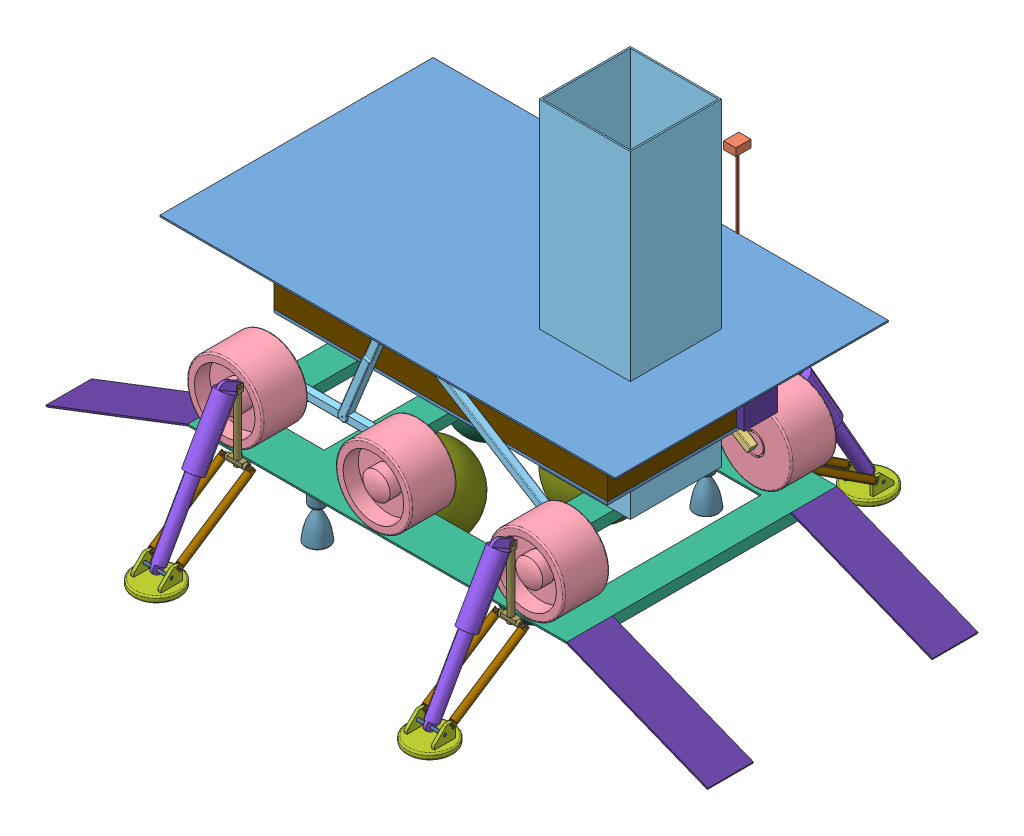
SolidWorks assembly Rover Lander assem_rev2, configuration Default. Lengths in mm.
Overall size (4365.19 2993.73 3190.9).
84 component instances, 35 part files, 46 mates.
Components (placement in the parent):
- Rover_base-1: Rover_base [Default] at (-1064.6676 -0.8898 562.4151) size (2200 20 1100)
- Neutron_spectrometer-1: Neutron_spectrometer [Default] at (-926.7762 19.1102 412.2415) size (300 57 300)
- Neutron_spectrometer_electronics-1: Neutron_spectrometer_electronics [Default] at (-591.6675 19.1102 476.7062) size (180 30 130)
- gc-1: gc [Default] at (-1085.6976 19.1102 139.436) size (100 80 100)
- svr_box-1: svr_box [Default] at (435.3324 -257.9063 312.4151) size (600 2100 600)
- xrf-1: xrf [Default] at (-995.9409 19.1102 -179.1913) size (80 90 80)
- geotechnical_exp-1: geotechnical_exp [Default] at (118.8439 19.1102 479.7148) x (0.999975 0 -0.007135) z (0.007135 0 0.999975) size (130 30 130)
- penetrometer_3-1: penetrometer_3 [Default] at (226.7911 19.1102 -521.6787) x (-0.361814 0 0.93225) z (-0.93225 0 -0.361814) size (20 40 20)
- penetrometer_3-2: penetrometer_3 [Default] at (171.3766 19.1102 -523.8951) size (20 40 20)
- penetrometer_3-3: penetrometer_3 [Default] at (128.071 19.1102 -518.5402) x (0.588244 0 -0.808683) z (0.808683 0 0.588244) size (20 40 20)
- power-1: power [Default] at (-492.3956 19.1102 -328.3877) size (180 90 96)
- geotechnical_exp_vane-1: geotechnical_exp_vane [Default] at (965.2252 19.1102 444.9326) size (220 40 220)
- Magnents-1: Magnents [Default] at (-1020.4169 -10.8898 98.2252) size (45 10 45)
- Becon-1: Becon [Default] at (656.9367 19.1102 515.9957) size (80 90 100)
- Belly Cam-1: Belly Cam [Default] at (-624.94 -100.8898 134.6139) size (150 100 150)
- lithium_battery_pack-1: lithium_battery_pack [Default] at (-598.6676 19.1102 301.6649) size (984 426 582)
- arm-1: arm [Default] at (-1208.8877 19.1102 -520.2644) x (-1 0 0) z (0 0 -1) size (1100 100 100)
- scoop-1: scoop [Default] at (-1258.8868 69.4182 -520.2644) x (0.225074 0.974342 0) z (0.974342 -0.225074 0) size (211.36 101.82 100)
- drill-1: drill [Default] at (1185.3324 19.1102 -287.5849) size (500 200 220)
- Rover_base_cover_rev2-1: Rover_base_cover_rev2 [Default] at (1135.3324 519.1102 -537.5849) x (1 0 0) z (0 0 -1) size (2200 500 1100)
- solar cell-1: solar cell [Default] at (-1464.6676 519.1102 -887.5849) x (-1 0 0) z (0 0 -1) size (3000 10 1800)
- stero_imaging_sys-1: stero_imaging_sys [Default] at (532.9681 509.1102 -537.5849) size (80 548.91 402.36)
- left_mobiiity_assemSLDASM-1: left_mobiiity_assemSLDASM [Default] at (441.8491 -164.5052 -588.2789) x (-1 0 0) z (0 0 -1) size (2690.28 1092.83 400.39)
  - Suspension arms-1: Suspension arms [Default] at (-510.2208 -182.1885 -50.694) size (2026.29 764.42 130)
  - wheel-1: wheel [Default] at (-506.5103 -152.4189 299.306) x (-0.792605 -0.609735 0) z (0 0 -1) size (500 500 300.39)
  - wheel-2: wheel [Default] at (1479.7792 -157.1885 299.306) x (-0.72713 -0.6865 0) z (0 0 -1) size (500 500 300.39)
  - wheel-3: wheel [Default] at (499.7792 -157.1885 299.306) x (-0.949229 -0.314586 0) z (0 0 -1) size (500 500 300.39)
- right_mobiiity_assemSLDASM-1: right_mobiiity_assemSLDASM [Default] at (616.3891 -382.4876 815.2315) x (-1 0 0) z (0 0 -1) size (2486.29 989.42 400.39)
  - Suspension arms_mirror-1: Suspension arms_mirror [Default] at (-335.6808 35.7938 152.8164) size (2026.29 764.42 130)
  - wheel-1: wheel [Default] at (1654.3192 60.7938 -97.1836) size (500 500 300.39)
  - wheel-2: wheel [Default] at (-331.9703 65.5634 -97.1836) size (500 500 300.39)
  - wheel-3: wheel [Default] at (674.3192 60.7938 -97.1836) size (500 500 300.39)
- lander_base_assem-1: lander_base_assem [Default] at (501.9744 -116.9076 976.2747) x (0.999997 0.002401 0) z (0 0 1) size (4362.63 1074.03 3190.9)
  - Lander base-1: Lander base [Default] at (714.6592 -461.0878 -63.8597) size (2500 70 1780)
  - leg_aluminum_rev-1: leg_aluminum_rev [Default] at (365.8635 -910.6524 482.3383) x (0 0.000985 1) z (-1 0 0) size (725.04 964.3 300)
    - base_leg-1: base_leg [Default] at (9.2435 -7.9699 0.537) size (300 140 300)
    - Main_leg-1: Main_leg [Default] at (-240.1972 521.872 0.537) x (0 0 -1) z (0.869495 0.493942 0) size (120 996.55 163.86)
    - Support_leg-1: Support_leg [Default] at (-74.206 133.9648 -89.463) x (0 0 -1) z (0.548366 0.836238 0) size (45 600 45)
    - leg_pin-1: leg_pin [Default] at (9.2435 82.777 -99.463) x (0 0 1) z (-0.667547 0.744568 0) size (200 20 20)
    - Support_leg-2: Support_leg [Default] at (-74.206 133.9648 90.537) x (0 0 -1) z (0.548366 0.836238 0) size (45 600 45)
    - leg_support_pin-1: leg_support_pin [Default] at (-40.7565 112.0301 -76.463) x (0 0 -1) z (1 0 0) size (26 10 10)
    - leg_support_pin-2: leg_support_pin [Default] at (-40.7565 112.0301 103.537) x (0 0 -1) z (1 0 0) size (26 10 10)
    - leg_joiner-1: leg_joiner [Default] at (-525.7944 410.0826 0.537) x (1 -0.000985 0) z (0 0 1) size (60 470.09 206)
    - leg_joiner_pin-1: leg_joiner_pin [Default] at (-525.3511 860.1724 -19.463) size (20 20 40)
  - leg_aluminum_rev-2: leg_aluminum_rev [Default] at (364.7896 -910.6524 -2390.0576) x (0 0.000985 -1) z (1 0 0) size (725.04 964.3 300)
    - base_leg-1: base_leg [Default] at (9.2435 -7.9699 0.537) size (300 140 300)
    - Main_leg-1: Main_leg [Default] at (-240.1972 521.872 0.537) x (0 0 -1) z (0.869495 0.493942 0) size (120 996.55 163.86)
    - Support_leg-1: Support_leg [Default] at (-74.206 133.9648 -89.463) x (0 0 -1) z (0.548366 0.836238 0) size (45 600 45)
    - leg_pin-1: leg_pin [Default] at (9.2435 82.777 -99.463) x (0 0 1) z (-0.667547 0.744568 0) size (200 20 20)
    - Support_leg-2: Support_leg [Default] at (-74.206 133.9648 90.537) x (0 0 -1) z (0.548366 0.836238 0) size (45 600 45)
    - leg_support_pin-1: leg_support_pin [Default] at (-40.7565 112.0301 -76.463) x (0 0 -1) z (1 0 0) size (26 10 10)
    - leg_support_pin-2: leg_support_pin [Default] at (-40.7565 112.0301 103.537) x (0 0 -1) z (1 0 0) size (26 10 10)
    - leg_joiner-1: leg_joiner [Default] at (-525.7944 410.0826 0.537) x (1 -0.000985 0) z (0 0 1) size (60 470.09 206)
    - leg_joiner_pin-1: leg_joiner_pin [Default] at (-525.3511 860.1724 -19.463) size (20 20 40)
  - leg_aluminum_rev-3: leg_aluminum_rev [Default] at (-1436.5452 -910.6524 -2390.0576) x (0 0.000985 -1) z (1 0 0) size (725.04 964.3 300)
    - base_leg-1: base_leg [Default] at (9.2435 -7.9699 0.537) size (300 140 300)
    - Main_leg-1: Main_leg [Default] at (-240.1972 521.872 0.537) x (0 0 -1) z (0.869495 0.493942 0) size (120 996.55 163.86)
    - Support_leg-1: Support_leg [Default] at (-74.206 133.9648 -89.463) x (0 0 -1) z (0.548366 0.836238 0) size (45 600 45)
    - leg_pin-1: leg_pin [Default] at (9.2435 82.777 -99.463) x (0 0 1) z (-0.667547 0.744568 0) size (200 20 20)
    - Support_leg-2: Support_leg [Default] at (-74.206 133.9648 90.537) x (0 0 -1) z (0.548366 0.836238 0) size (45 600 45)
    - leg_support_pin-1: leg_support_pin [Default] at (-40.7565 112.0301 -76.463) x (0 0 -1) z (1 0 0) size (26 10 10)
    - leg_support_pin-2: leg_support_pin [Default] at (-40.7565 112.0301 103.537) x (0 0 -1) z (1 0 0) size (26 10 10)
    - leg_joiner-1: leg_joiner [Default] at (-525.7944 410.0826 0.537) x (1 -0.000985 0) z (0 0 1) size (60 470.09 206)
    - leg_joiner_pin-1: leg_joiner_pin [Default] at (-525.3511 860.1724 -19.463) size (20 20 40)
  - leg_aluminum_rev-4: leg_aluminum_rev [Default] at (-1435.4713 -910.6524 482.3383) x (0 0.000985 1) z (-1 0 0) size (725.04 964.3 300)
    - base_leg-1: base_leg [Default] at (9.2435 -7.9699 0.537) size (300 140 300)
    - Main_leg-1: Main_leg [Default] at (-240.1972 521.872 0.537) x (0 0 -1) z (0.869495 0.493942 0) size (120 996.55 163.86)
    - Support_leg-1: Support_leg [Default] at (-74.206 133.9648 -89.463) x (0 0 -1) z (0.548366 0.836238 0) size (45 600 45)
    - leg_pin-1: leg_pin [Default] at (9.2435 82.777 -99.463) x (0 0 1) z (-0.667547 0.744568 0) size (200 20 20)
    - Support_leg-2: Support_leg [Default] at (-74.206 133.9648 90.537) x (0 0 -1) z (0.548366 0.836238 0) size (45 600 45)
    - leg_support_pin-1: leg_support_pin [Default] at (-40.7565 112.0301 -76.463) x (0 0 -1) z (1 0 0) size (26 10 10)
    - leg_support_pin-2: leg_support_pin [Default] at (-40.7565 112.0301 103.537) x (0 0 -1) z (1 0 0) size (26 10 10)
    - leg_joiner-1: leg_joiner [Default] at (-525.7944 410.0826 0.537) x (1 -0.000985 0) z (0 0 1) size (60 470.09 206)
    - leg_joiner_pin-1: leg_joiner_pin [Default] at (-525.3511 860.1724 -19.463) size (20 20 40)
  - MR_80b-1: MR_80b [Default] at (-1081.6322 -841.0878 -214.0715) size (153.97 380 153.97)
  - MR_80b-2: MR_80b [Default] at (16.7233 -838.4394 -1679.7382) x (0.999992 0 0.004071) z (-0.004071 0 0.999992) size (153.97 380 153.97)
  - Helium_tank-1: Helium_tank [Default] at (203.1711 -638.5192 -541.9795) x (0.94256 0.329358 0.055716) z (0.325345 -0.942975 0.070353) size (400 400 400)
  - Helium_tank-2: Helium_tank [Default] at (-953.3371 -635.4687 -1361.8199) x (0.977489 0.124684 0.170201) z (-0.107578 -0.399417 0.910436) size (400 400 400)
  - Hydrazine_tank-1: Hydrazine_tank [Default] at (-643.5463 -334.2768 -539.5578) x (0.363071 0.900077 0.240916) z (0.071543 0.230867 -0.970352) size (550 550 550)
  - Hydrazine_tank-2: Hydrazine_tank [Default] at (-75.2899 -529.4709 -1409.1331) x (0.901296 0.217178 -0.374832) z (0.418463 -0.660267 0.623647) size (550 550 550)
  - ramp-1: ramp [Default] at (-1781.7357 -460.4154 -1543.8597) x (0.932756 0.360509 0) z (0 0 1) size (1000 10 300)
  - ramp-2: ramp [Default] at (-1781.7786 -460.4318 -63.8597) x (0.934403 0.356219 0) z (0 0 1) size (1000 10 300)
  - ramp-3: ramp [Default] at (1639.1629 -832.3921 -1543.8597) x (0.928224 -0.372022 0) z (0 0 1) size (1000 10 300)
  - ramp-4: ramp [Default] at (1639.0067 -832.7706 -63.8597) x (0.928071 -0.372402 0) z (0 0 1) size (1000 10 300)
Mates (geometry in assembly coordinates):
- Coincident2: coincident anti-aligned: plane of Rover_base-1 through (-1064.6676 19.1102 -537.5849) normal (0 1 0); plane of Neutron_spectrometer-1 through (-926.7762 19.1102 412.2415) normal (0 -1 0)
- Coincident6: coincident anti-aligned: plane of Rover_base-1 through (-1064.6676 19.1102 -537.5849) normal (0 1 0); plane of Neutron_spectrometer_electronics-1 through (-591.6675 19.1102 346.7062) normal (0 -1 0)
- Coincident7: coincident anti-aligned: plane of Rover_base-1 through (-1064.6676 19.1102 -537.5849) normal (0 1 0); plane of power-1 through (-492.3956 19.1102 -424.3877) normal (0 -1 0)
- Coincident8: coincident anti-aligned: plane of Rover_base-1 through (-1064.6676 19.1102 -537.5849) normal (0 1 0); plane of gc-1 through (-1085.6976 19.1102 39.436) normal (0 -1 0)
- Coincident9: coincident aligned: plane of Rover_base-1 through (-1064.6676 19.1102 -537.5849) normal (0 1 0); circle of geotechnical_exp-1 centre (118.8439 19.1102 479.7148) axis (0 1 0)
- Coincident10: coincident anti-aligned: plane of Rover_base-1 through (-1064.6676 19.1102 -537.5849) normal (0 1 0); plane of xrf-1 through (-995.9409 19.1102 -179.1913) normal (0 -1 0)
- Coincident11: coincident aligned: plane of Rover_base-1 through (-1064.6676 19.1102 -537.5849) normal (0 1 0); circle of penetrometer_3-3 centre (128.071 19.1102 -518.5402) axis (0 1 0)
- Coincident12: coincident anti-aligned: plane of Rover_base-1 through (-1064.6676 19.1102 -537.5849) normal (0 1 0); plane of penetrometer_3-2 through (171.3766 19.1102 -523.8951) normal (0 -1 0)
- Coincident13: coincident aligned: plane of Rover_base-1 through (-1064.6676 19.1102 -537.5849) normal (0 1 0); circle of penetrometer_3-1 centre (226.7911 19.1102 -521.6787) axis (0 1 0)
- Coincident14: coincident anti-aligned: plane of Rover_base-1 through (-1064.6676 19.1102 -537.5849) normal (0 1 0); plane of geotechnical_exp_vane-1 through (965.2252 19.1102 444.9326) normal (0 -1 0)
- Coincident15: coincident anti-aligned: plane of Rover_base-1 through (-1064.6676 -0.8898 -537.5849) normal (0 -1 0); plane of Magnents-1 through (-1020.4169 -0.8898 98.2252) normal (0 1 0)
- Coincident16: coincident anti-aligned: plane of Rover_base-1 through (-1064.6676 19.1102 -537.5849) normal (0 1 0); plane of Becon-1 through (656.9367 19.1102 515.9957) normal (0 -1 0)
- Coincident18: coincident: line of Rover_base-1; plane of svr_box-1 through (435.3324 1842.0937 312.4151) normal (-1 0 0)
- Coincident20: coincident: line of Rover_base-1; plane of svr_box-1 through (435.3324 1842.0937 -287.5849) normal (0 0 -1)
- Perpendicular2: perpendicular: line of Rover_base-1; line of svr_box-1
- Perpendicular3: perpendicular: line of Rover_base-1; line of svr_box-1
- Perpendicular4: perpendicular: line of Rover_base-1; line of svr_box-1
- Coincident21: coincident anti-aligned: plane of Rover_base-1 through (-1064.6676 19.1102 -537.5849) normal (0 1 0); plane of lithium_battery_pack-1 through (-598.6676 19.1102 -280.3351) normal (0 -1 0)
- Distance1: distance = 50 mm anti-aligned: plane of svr_box-1 through (435.3324 1842.0937 312.4151) normal (-1 0 0); plane of lithium_battery_pack-1 through (385.3324 445.1102 301.6649) normal (1 0 0)
- Coincident23: coincident anti-aligned: plane of Rover_base-1 through (-1064.6676 19.1102 -537.5849) normal (0 1 0); plane of arm-1 through (-1208.8877 19.1102 -420.2644) normal (0 -1 0)
- Distance2: distance = 100 mm: line of Rover_base-1; point of arm-1
- Distance3: distance = 20 mm: line of Rover_base-1; line of arm-1
- Coincident27: coincident aligned: circle of arm-1 centre (-1208.8877 69.1102 -470.2644) axis (0 0 1); circle of scoop-1 centre (-1208.8877 69.1102 -470.2644) axis (0 0 1)
- Coincident28: coincident anti-aligned: plane of Rover_base-1 through (-1064.6676 19.1102 -537.5849) normal (0 1 0); plane of drill-1 through (1185.3324 19.1102 -507.5849) normal (0 -1 0)
- Coincident29: coincident anti-aligned: plane of svr_box-1 through (435.3324 1842.0937 -287.5849) normal (0 0 -1); plane of drill-1 through (1185.3324 219.1102 -287.5849) normal (0 0 1)
- Distance4: distance = 50 mm: line of Rover_base-1; plane of drill-1 through (1185.3324 219.1102 -287.5849) normal (1 0 0)
- Coincident30: coincident anti-aligned: plane of svr_box-1 through (435.3324 1842.0937 312.4151) normal (-1 0 0); plane of Rover_base_cover_rev2-1 through (435.3324 119.1102 -287.5849) normal (1 0 0)
- Coincident31: coincident anti-aligned: plane of svr_box-1 through (435.3324 1842.0937 312.4151) normal (0 0 1); plane of Rover_base_cover_rev2-1 through (1035.3324 119.1102 312.4151) normal (0 0 -1)
- Coincident32: coincident anti-aligned: plane of Rover_base-1 through (-1064.6676 19.1102 -537.5849) normal (0 1 0); plane of Rover_base_cover_rev2-1 through (1135.3324 19.1102 562.4151) normal (0 -1 0)
- Coincident33: coincident anti-aligned: plane of Rover_base_cover_rev2-1 through (1135.3324 519.1102 562.4151) normal (0 1 0); plane of solar cell-1 through (-1464.6676 519.1102 -887.5849) normal (0 -1 0)
- Coincident34: coincident anti-aligned: plane of svr_box-1 through (435.3324 1842.0937 312.4151) normal (-1 0 0); plane of solar cell-1 through (435.3324 519.1102 -287.5849) normal (1 0 0)
- Coincident35: coincident anti-aligned: plane of svr_box-1 through (435.3324 1842.0937 312.4151) normal (0 0 1); plane of solar cell-1 through (435.3324 519.1102 312.4151) normal (0 0 -1)
- Coincident36: coincident anti-aligned: plane of Rover_base_cover_rev2-1 through (1135.3324 19.1102 -537.5849) normal (0 0 -1); plane of stero_imaging_sys-1 through (542.9681 519.1102 -537.5849) normal (0 0 1)
- Coincident37: coincident anti-aligned: plane of solar cell-1 through (-1464.6676 519.1102 -887.5849) normal (0 -1 0); plane of stero_imaging_sys-1 through (542.9681 519.1102 -884.9456) normal (0 1 0)
- Coincident38: coincident anti-aligned: plane of Rover_base_cover_rev2-1 through (1135.3324 19.1102 -537.5849) normal (0 0 -1); plane of left_mobiiity_assemSLDASM-1/Suspension arms-1 through (-219.8802 310.8016 -537.5849) normal (0 0 1)
- Parallel1: parallel anti-aligned: line of Rover_base-1; line of left_mobiiity_assemSLDASM-1/Suspension arms-1
- Distance7: distance = 650 mm: line of Rover_base_cover_rev2-1; point of left_mobiiity_assemSLDASM-1/Suspension arms-1
- Coincident43: coincident anti-aligned: plane of Rover_base_cover_rev2-1 through (1135.3324 19.1102 562.4151) normal (0 0 1); plane of right_mobiiity_assemSLDASM-1/Suspension arms_mirror-1 through (-219.8802 310.8016 562.4151) normal (0 0 -1)
- Parallel2: parallel anti-aligned: line of Rover_base-1; line of right_mobiiity_assemSLDASM-1/Suspension arms_mirror-1
- Distance8: distance = 300 mm: line of Rover_base-1; line of right_mobiiity_assemSLDASM-1/Suspension arms_mirror-1
- Distance9: distance = 650 mm: line of Rover_base_cover_rev2-1; point of right_mobiiity_assemSLDASM-1/Suspension arms_mirror-1
- Coincident44: coincident aligned: plane of right_mobiiity_assemSLDASM-1/wheel-1 through (-1037.9301 -321.6938 912.4151) normal (0 0 1); plane of lander_base_assem-1/Lander base-1 through (1217.7147 -566.278 912.4151) normal (0 0 1)
- Tangent1: tangent anti-aligned: cylinder of left_mobiiity_assemSLDASM-1/wheel-2; plane of lander_base_assem-1/Lander base-1 through (1217.7147 -566.278 912.4151) normal (-0.002401 0.999997 0)
- Tangent3: tangent anti-aligned: cylinder of right_mobiiity_assemSLDASM-1/wheel-2; plane of lander_base_assem-1/Lander base-1 through (1217.7147 -566.278 912.4151) normal (-0.002401 0.999997 0)
- Distance10: distance = 300 mm: line of Rover_base-1; line of left_mobiiity_assemSLDASM-1/Suspension arms-1
- Distance11: distance = 350 mm: point of right_mobiiity_assemSLDASM-1/wheel-1; line of lander_base_assem-1/Lander base-1
